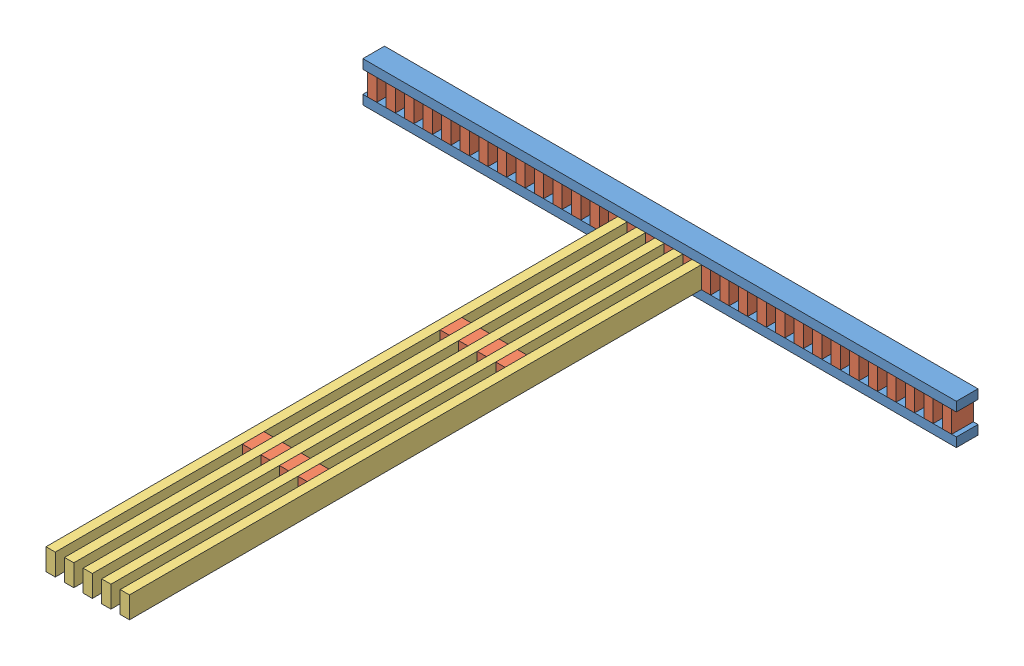
SolidWorks assembly foot_plus_side_post, configuration Default. Lengths in mm.
Overall size (2438.4 165.1 2438.4).
51 component instances, 3 part files, 9 mates.
Components (placement in the parent):
- foot_post-1: foot_post [Default] at (1347.1514 1068.5792 1779.6361) size (2438.4 165.1 88.9)
  - 2x4_foot-1: 2x4_foot [Default] at (-704.8006 1778.2043 2380.3143) size (2438.4 38.1 88.9)
  - 2x4_foot-2: 2x4_foot [Default] at (-704.8006 1689.3043 2469.2143) x (1 0 0) z (0 0 -1) size (2438.4 38.1 88.9)
  - 4x4x2_gusset-32: 4x4x2_gusset [Default] at (571.5494 1689.3043 2380.3143) x (0 1 0) z (0 0 1) size (88.9 38.1 88.9)
  - 4x4x2_gusset-33: 4x4x2_gusset [Default] at (495.3494 1689.3043 2380.3143) x (0 1 0) z (0 0 1) size (88.9 38.1 88.9)
  - 4x4x2_gusset-34: 4x4x2_gusset [Default] at (419.1494 1689.3043 2380.3143) x (0 1 0) z (0 0 1) size (88.9 38.1 88.9)
  - 4x4x2_gusset-35: 4x4x2_gusset [Default] at (342.9494 1689.3043 2380.3143) x (0 1 0) z (0 0 1) size (88.9 38.1 88.9)
  - 4x4x2_gusset-36: 4x4x2_gusset [Default] at (266.7494 1689.3043 2380.3143) x (0 1 0) z (0 0 1) size (88.9 38.1 88.9)
  - 4x4x2_gusset-37: 4x4x2_gusset [Default] at (190.5494 1689.3043 2380.3143) x (0 1 0) z (0 0 1) size (88.9 38.1 88.9)
  - 4x4x2_gusset-38: 4x4x2_gusset [Default] at (114.3494 1689.3043 2380.3143) x (0 1 0) z (0 0 1) size (88.9 38.1 88.9)
  - 4x4x2_gusset-39: 4x4x2_gusset [Default] at (38.1494 1689.3043 2380.3143) x (0 1 0) z (0 0 1) size (88.9 38.1 88.9)
  - 4x4x2_gusset-40: 4x4x2_gusset [Default] at (-38.0506 1689.3043 2380.3143) x (0 1 0) z (0 0 1) size (88.9 38.1 88.9)
  - 4x4x2_gusset-41: 4x4x2_gusset [Default] at (-114.2506 1689.3043 2380.3143) x (0 1 0) z (0 0 1) size (88.9 38.1 88.9)
  - 4x4x2_gusset-42: 4x4x2_gusset [Default] at (-190.4506 1689.3043 2380.3143) x (0 1 0) z (0 0 1) size (88.9 38.1 88.9)
  - 4x4x2_gusset-43: 4x4x2_gusset [Default] at (-266.6506 1689.3043 2380.3143) x (0 1 0) z (0 0 1) size (88.9 38.1 88.9)
  - 4x4x2_gusset-44: 4x4x2_gusset [Default] at (-342.8506 1689.3043 2380.3143) x (0 1 0) z (0 0 1) size (88.9 38.1 88.9)
  - 4x4x2_gusset-45: 4x4x2_gusset [Default] at (-419.0506 1689.3043 2380.3143) x (0 1 0) z (0 0 1) size (88.9 38.1 88.9)
  - 4x4x2_gusset-46: 4x4x2_gusset [Default] at (-495.2506 1689.3043 2380.3143) x (0 1 0) z (0 0 1) size (88.9 38.1 88.9)
  - 4x4x2_gusset-47: 4x4x2_gusset [Default] at (-571.4506 1689.3043 2380.3143) x (0 1 0) z (0 0 1) size (88.9 38.1 88.9)
  - 4x4x2_gusset-48: 4x4x2_gusset [Default] at (-647.6506 1689.3043 2380.3143) x (0 1 0) z (0 0 1) size (88.9 38.1 88.9)
  - 4x4x2_gusset-49: 4x4x2_gusset [Default] at (647.7494 1689.3043 2380.3143) x (0 1 0) z (0 0 1) size (88.9 38.1 88.9)
  - 4x4x2_gusset-50: 4x4x2_gusset [Default] at (723.9494 1689.3043 2380.3143) x (0 1 0) z (0 0 1) size (88.9 38.1 88.9)
  - 4x4x2_gusset-51: 4x4x2_gusset [Default] at (800.1494 1689.3043 2380.3143) x (0 1 0) z (0 0 1) size (88.9 38.1 88.9)
  - 4x4x2_gusset-52: 4x4x2_gusset [Default] at (876.3494 1689.3043 2380.3143) x (0 1 0) z (0 0 1) size (88.9 38.1 88.9)
  - 4x4x2_gusset-53: 4x4x2_gusset [Default] at (952.5494 1689.3043 2380.3143) x (0 1 0) z (0 0 1) size (88.9 38.1 88.9)
  - 4x4x2_gusset-54: 4x4x2_gusset [Default] at (1028.7494 1689.3043 2380.3143) x (0 1 0) z (0 0 1) size (88.9 38.1 88.9)
  - 4x4x2_gusset-55: 4x4x2_gusset [Default] at (1104.9494 1689.3043 2380.3143) x (0 1 0) z (0 0 1) size (88.9 38.1 88.9)
  - 4x4x2_gusset-56: 4x4x2_gusset [Default] at (1181.1494 1689.3043 2380.3143) x (0 1 0) z (0 0 1) size (88.9 38.1 88.9)
  - 4x4x2_gusset-57: 4x4x2_gusset [Default] at (1257.3494 1689.3043 2380.3143) x (0 1 0) z (0 0 1) size (88.9 38.1 88.9)
  - 4x4x2_gusset-58: 4x4x2_gusset [Default] at (1333.5494 1689.3043 2380.3143) x (0 1 0) z (0 0 1) size (88.9 38.1 88.9)
  - 4x4x2_gusset-59: 4x4x2_gusset [Default] at (1409.7494 1689.3043 2380.3143) x (0 1 0) z (0 0 1) size (88.9 38.1 88.9)
  - 4x4x2_gusset-60: 4x4x2_gusset [Default] at (1485.9494 1689.3043 2380.3143) x (0 1 0) z (0 0 1) size (88.9 38.1 88.9)
  - 4x4x2_gusset-61: 4x4x2_gusset [Default] at (1562.1494 1689.3043 2380.3143) x (0 1 0) z (0 0 1) size (88.9 38.1 88.9)
  - 4x4x2_gusset-62: 4x4x2_gusset [Default] at (1638.3494 1689.3043 2380.3143) x (0 1 0) z (0 0 1) size (88.9 38.1 88.9)
  - 4x4x2_gusset-63: 4x4x2_gusset [Default] at (1714.5494 1689.3043 2380.3143) x (0 1 0) z (0 0 1) size (88.9 38.1 88.9)
- 18x4_female_post-1: 18x4_female_post [Default] at (4665.928 6948.7926 3132.4615) x (0 0 1) z (0 -1 0) size (2438.4 342.9 88.9)
  - 6x4_female_post-1: 6x4_female_post [Default] at (1617.4053 951.3945 1716.6403) size (2438.4 114.3 88.9)
    - 2x4-1: 2x4 [Default] at (-589.9165 1681.5327 2385.3688) size (2438.4 38.1 88.9)
    - 4x4x2_gusset-1: 4x4x2_gusset [Default] at (178.4335 1719.6327 2385.3688) size (88.9 38.1 88.9)
    - 4x4x2_gusset-2: 4x4x2_gusset [Default] at (991.2335 1719.6327 2385.3688) size (88.9 38.1 88.9)
    - 2x4-2: 2x4 [Default] at (-589.9165 1757.7327 2385.3688) size (2438.4 38.1 88.9)
  - 6x4_female_post-2: 6x4_female_post [Default] at (1617.4053 1103.7945 1716.6403) size (2438.4 114.3 88.9)
    - 2x4-1: 2x4 [Default] at (-589.9165 1681.5327 2385.3688) size (2438.4 38.1 88.9)
    - 4x4x2_gusset-1: 4x4x2_gusset [Default] at (178.4335 1719.6327 2385.3688) size (88.9 38.1 88.9)
    - 4x4x2_gusset-2: 4x4x2_gusset [Default] at (991.2335 1719.6327 2385.3688) size (88.9 38.1 88.9)
    - 2x4-2: 2x4 [Default] at (-589.9165 1757.7327 2385.3688) size (2438.4 38.1 88.9)
  - 4x4x2_gusset-1: 4x4x2_gusset [Default] at (1795.8388 2747.2272 4102.0091) size (88.9 38.1 88.9)
  - 4x4x2_gusset-2: 4x4x2_gusset [Default] at (2608.6388 2747.2272 4102.0091) size (88.9 38.1 88.9)
  - 2x4-1: 2x4 [Default] at (1027.4888 2937.7272 4102.0091) size (2438.4 38.1 88.9)
  - 4x4x2_gusset-3: 4x4x2_gusset [Default] at (1795.8388 2899.6272 4102.0091) size (88.9 38.1 88.9)
  - 4x4x2_gusset-4: 4x4x2_gusset [Default] at (2608.6388 2899.6272 4102.0091) size (88.9 38.1 88.9)
Mates (geometry in assembly coordinates):
- Coincident1: coincident: plane of ? through (1880.6008 2757.8835 4159.9504) normal (1 0 0); plane of ? through (1880.6008 2846.7835 4159.9504) normal (-1 0 0)
- Coincident2: coincident: plane of foot_post-1/2x4_foot-2 through (642.3508 2719.7835 4159.9504) normal (0 0 -1); plane of ? through (1956.8008 2846.7835 4159.9504) normal (0 0 -1)
- Coincident3: coincident: plane of foot_post-1/2x4_foot-1 through (642.3508 2846.7835 4159.9504) normal (0 -1 0); plane of ? through (1956.8008 2846.7835 4159.9504) normal (0 1 0)
- Coincident4: coincident: plane of foot_post-1/4x4x2_gusset-33 through (1842.5008 2757.8835 4159.9504) normal (1 0 0); plane of 18x4_female_post-1/6x4_female_post-2/2x4-1 through (1842.5008 2846.7835 4159.9504) normal (-1 0 0)
- Coincident5: coincident: plane of foot_post-1/2x4_foot-2 through (642.3508 2719.7835 4159.9504) normal (0 0 -1); plane of 18x4_female_post-1/6x4_female_post-2/2x4-1 through (1842.5008 2846.7835 4159.9504) normal (0 0 -1)
- Coincident7: coincident: plane of foot_post-1/2x4_foot-1 through (642.3508 2846.7835 4159.9504) normal (0 -1 0); plane of 18x4_female_post-1/6x4_female_post-2/2x4-1 through (1842.5008 2846.7835 4159.9504) normal (0 1 0)
- Coincident8: coincident: plane of 18x4_female_post-1/2x4-1 through (1728.2008 2846.7835 4159.9504) normal (1 0 0); plane of ? through (1728.2008 2884.8835 4248.8504) normal (-1 0 0)
- Coincident9: coincident: plane of foot_post-1/2x4_foot-2 through (642.3508 2719.7835 4248.8504) normal (0 0 1); plane of ? through (1766.3008 2884.8835 4248.8504) normal (0 0 -1)
- Coincident10: coincident: plane of foot_post-1/2x4_foot-1 through (642.3508 2884.8835 4159.9504) normal (0 1 0); plane of ? through (1766.3008 2884.8835 4248.8504) normal (0 1 0)
